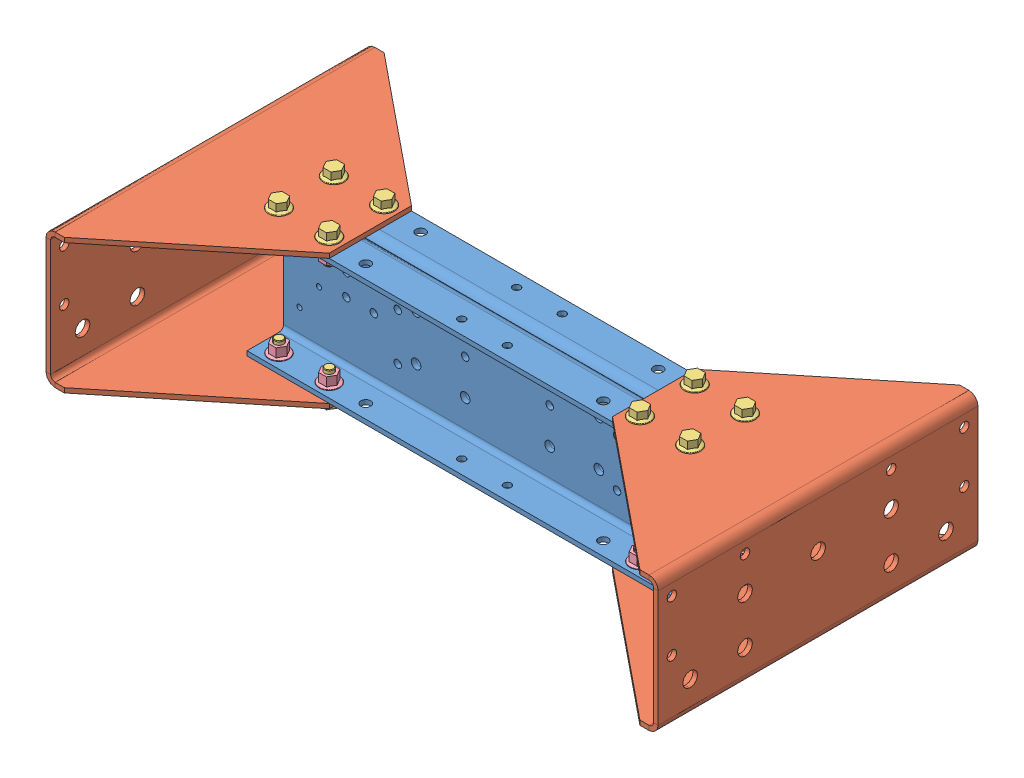
SolidWorks assembly SUB-1700-073, configuration Collapsed. Lengths in mm.
Overall size (850.9 213.23 444.5).
36 component instances, 4 part files, 109 mates.
Components (placement in the parent):
- 2504-CC2-1: 2504-CC2 [Default] at origin size (622.3 174.62 57.15)
- 2504-CC2-2: 2504-CC2 [Default] x (-1 0 0) z (0 0 -1) size (622.3 174.62 57.15)
- 2522-CC2-4: 2522-CC2 [2522-CC2-001] at (425.45 0 0) size (228.6 187.33 444.5)
- 2522-CC2-5: 2522-CC2 [2522-CC2-001] at (-425.45 0 0) x (-1 0 0) z (0 0 -1) size (228.6 187.33 444.5)
- 08130XXXFH8Y-35: 08130XXXFH8Y [08130125FH8Y] at (215.9 -93.6625 38.1) x (-0.866025 0 -0.5) z (0 -1 0) size (28.77 28.77 44.7)
- 08130XXXFH8Y-37: 08130XXXFH8Y [08130125FH8Y] at (-215.9 -93.6625 38.1) x (-0.866025 0 -0.5) z (0 -1 0) size (28.77 28.77 44.7)
- 08130XXXFH8Y-40: 08130XXXFH8Y [08130125FH8Y] at (-215.9 -93.6625 -38.1) x (-0.866025 0 -0.5) z (0 -1 0) size (28.77 28.77 44.7)
- 08130XXXFH8Y-38: 08130XXXFH8Y [08130125FH8Y] at (-215.9 93.6625 38.1) x (-0.866025 0 -0.5) z (0 1 0) size (28.77 28.77 44.7)
- 08130XXXFH8Y-34: 08130XXXFH8Y [08130125FH8Y] at (215.9 93.6625 -38.1) x (0 0 -1) z (0 1 0) size (28.77 28.77 44.7)
- 08130XXXFH8Y-33: 08130XXXFH8Y [08130125FH8Y] at (215.9 -93.6625 -38.1) x (-0.866025 0 -0.5) z (0 -1 0) size (28.77 28.77 44.7)
- 08130XXXFH8Y-36: 08130XXXFH8Y [08130125FH8Y] at (215.9 93.6625 38.1) x (0 0 -1) z (0 1 0) size (28.77 28.77 44.7)
- 08130XXXFH8Y-39: 08130XXXFH8Y [08130125FH8Y] at (-215.9 93.6625 -38.1) x (-0.866025 0 -0.5) z (0 1 0) size (28.77 28.77 44.7)
- XXXXFLN8Y-9: XXXXFLN8Y [0813FLN8Y] at (-285.75 80.9625 38.1) x (-0.866025 0 -0.5) z (0 -1 0) size (28.18 28.18 14.1)
- XXXXFLN8Y-5: XXXXFLN8Y [0813FLN8Y] at (-285.75 -80.9625 -38.1) x (0 0 -1) z (0 1 0) size (28.18 28.18 14.1)
- XXXXFLN8Y-11: XXXXFLN8Y [0813FLN8Y] at (-215.9 80.9625 38.1) x (-0.866025 0 -0.5) z (0 -1 0) size (28.18 28.18 14.1)
- XXXXFLN8Y-6: XXXXFLN8Y [0813FLN8Y] at (-285.75 -80.9625 38.1) x (0 0 -1) z (0 1 0) size (28.18 28.18 14.1)
- XXXXFLN8Y-10: XXXXFLN8Y [0813FLN8Y] at (-215.9 80.9625 -38.1) x (0.866025 0 -0.5) z (0 -1 0) size (28.18 28.18 14.1)
- XXXXFLN8Y-8: XXXXFLN8Y [0813FLN8Y] at (-285.75 80.9625 -38.1) x (-0.866025 0 -0.5) z (0 -1 0) size (28.18 28.18 14.1)
- XXXXFLN8Y-2: XXXXFLN8Y [0813FLN8Y] at (-215.9 -80.9625 -38.1) x (0.866025 0 -0.5) z (0 1 0) size (28.18 28.18 14.1)
- XXXXFLN8Y-4: XXXXFLN8Y [0813FLN8Y] at (215.9 -80.9625 38.1) x (0 0 -1) z (0 1 0) size (28.18 28.18 14.1)
- XXXXFLN8Y-15: XXXXFLN8Y [0813FLN8Y] at (285.75 80.9625 -38.1) x (0 0 -1) z (0 -1 0) size (28.18 28.18 14.1)
- XXXXFLN8Y-1: XXXXFLN8Y [0813FLN8Y] at (215.9 80.9625 -38.1) x (0 0 -1) z (0 -1 0) size (28.18 28.18 14.1)
- XXXXFLN8Y-3: XXXXFLN8Y [0813FLN8Y] at (215.9 -80.9625 -38.1) x (0 0 -1) z (0 1 0) size (28.18 28.18 14.1)
- XXXXFLN8Y-16: XXXXFLN8Y [0813FLN8Y] at (285.75 80.9625 38.1) x (0 0 -1) z (0 -1 0) size (28.18 28.18 14.1)
- XXXXFLN8Y-12: XXXXFLN8Y [0813FLN8Y] at (-215.9 -80.9625 38.1) x (0 0 -1) z (0 1 0) size (28.18 28.18 14.1)
- XXXXFLN8Y-13: XXXXFLN8Y [0813FLN8Y] at (285.75 -80.9625 38.1) x (0 0 -1) z (0 1 0) size (28.18 28.18 14.1)
- XXXXFLN8Y-7: XXXXFLN8Y [0813FLN8Y] at (215.9 80.9625 38.1) x (0 0 -1) z (0 -1 0) size (28.18 28.18 14.1)
- XXXXFLN8Y-14: XXXXFLN8Y [0813FLN8Y] at (285.75 -80.9625 -38.1) x (0 0 -1) z (0 1 0) size (28.18 28.18 14.1)
- 08130XXXFH8Y-26: 08130XXXFH8Y [08130125FH8Y] at (-285.75 -93.6625 38.1) x (-0.866025 0 -0.5) z (0 -1 0) size (28.77 28.77 44.7)
- 08130XXXFH8Y-41: 08130XXXFH8Y [08130125FH8Y] at (-285.75 -93.6625 -38.1) x (-0.866025 0 -0.5) z (0 -1 0) size (28.77 28.77 44.7)
- 08130XXXFH8Y-42: 08130XXXFH8Y [08130125FH8Y] at (-285.75 93.6625 38.1) x (-0.866025 0 -0.5) z (0 1 0) size (28.77 28.77 44.7)
- 08130XXXFH8Y-43: 08130XXXFH8Y [08130125FH8Y] at (-285.75 93.6625 -38.1) x (-0.866025 0 -0.5) z (0 1 0) size (28.77 28.77 44.7)
- 08130XXXFH8Y-44: 08130XXXFH8Y [08130125FH8Y] at (285.75 93.6625 38.1) x (0 0 -1) z (0 1 0) size (28.77 28.77 44.7)
- 08130XXXFH8Y-45: 08130XXXFH8Y [08130125FH8Y] at (285.75 93.6625 -38.1) x (0 0 -1) z (0 1 0) size (28.77 28.77 44.7)
- 08130XXXFH8Y-46: 08130XXXFH8Y [08130125FH8Y] at (285.75 -93.6625 -38.1) x (-0.866025 0 -0.5) z (0 -1 0) size (28.77 28.77 44.7)
- 08130XXXFH8Y-47: 08130XXXFH8Y [08130125FH8Y] at (285.75 -93.6625 38.1) x (-0.866025 0 -0.5) z (0 -1 0) size (28.77 28.77 44.7)
Mates (geometry in assembly coordinates):
- Coincident1: coincident aligned: plane of 2504-CC2-1 through (0 0 0) normal (0 0 1)
- Coincident88: coincident aligned: unknown of 2504-CC2-1
- Coincident3: coincident aligned: unknown of 2504-CC2-1
- Concentric31: concentric anti-aligned: cylinder of ?; circle of ?
- Concentric32: concentric anti-aligned: cylinder of ?; circle of ?
- Concentric33: concentric anti-aligned: cylinder of ?; circle of ?
- Concentric35: concentric anti-aligned: cylinder of ?; circle of ?
- Concentric36: concentric anti-aligned: cylinder of ?; circle of ?
- Concentric37: concentric anti-aligned: cylinder of ?; circle of ?
- Concentric38: concentric anti-aligned: cylinder of ?; circle of ?
- Concentric39: concentric anti-aligned: cylinder of ?; circle of ?
- Parallel7: parallel aligned: plane of ?; plane of ?
- Parallel8: parallel aligned: plane of ?; plane of ?
- Parallel9: parallel aligned: plane of ?; plane of ?
- Parallel10: parallel aligned: plane of ?; plane of ?
- Parallel11: parallel anti-aligned: plane of ?; plane of ?
- Parallel12: parallel aligned: plane of ?; plane of ?
- Parallel13: parallel aligned: plane of ?; plane of ?
- Parallel14: parallel aligned: plane of ?; plane of ?
- Parallel15: parallel anti-aligned: plane of ?; plane of ?
- Parallel16: parallel aligned: plane of ?; plane of ?
- Parallel18: parallel aligned: plane of ?; plane of ?
- Parallel20: parallel aligned: plane of ?; plane of ?
- Parallel21: parallel aligned: plane of ?; plane of ?
- Parallel24: parallel aligned: plane of ?; plane of ?
- Parallel25: parallel aligned: plane of ?; plane of ?
- Parallel26: parallel aligned: plane of ?; plane of ?
- Parallel27: parallel aligned: plane of ?; plane of ?
- Parallel28: parallel aligned: plane of ?; plane of ?
- Parallel30: parallel aligned: plane of ?; plane of ?
- Parallel33: parallel aligned: plane of ?; plane of ?
- Parallel34: parallel aligned: plane of ?; plane of ?
- Parallel35: parallel aligned: plane of ?; plane of ?
- Parallel36: parallel aligned: plane of ?; plane of ?
- Coincident57: coincident aligned: plane of 2504-CC2-1 through (0 0 0) normal (0 1 0); plane of 2504-CC2-2 through (0 0 0) normal (0 1 0)
- Coincident58: coincident anti-aligned: plane of 2504-CC2-1 through (0 0 0) normal (1 0 0); plane of 2504-CC2-2 through (0 0 0) normal (-1 0 0)
- Concentric40: concentric aligned: unknown of 2522-CC2-5
- Concentric41: concentric aligned: unknown of 2522-CC2-5
- Coincident66: coincident aligned: plane of ?; plane of ?
- Coincident67: coincident aligned: plane of ?; plane of ?
- Coincident68: coincident aligned: plane of ?; plane of ?
- Coincident70: coincident anti-aligned: unknown of 2504-CC2-2
- Concentric42: concentric anti-aligned: unknown of 2522-CC2-5
- Coincident71: coincident aligned: plane of ?; plane of ?
- Coincident72: coincident aligned: plane of ?; plane of ?
- Coincident73: coincident aligned: plane of ?; plane of ?
- Coincident74: coincident anti-aligned: unknown of 2504-CC2-1
- Concentric43: concentric anti-aligned: unknown of 2522-CC2-5
- Concentric44: concentric aligned: unknown of 2522-CC2-4
- Concentric47: concentric aligned: unknown of 2522-CC2-4
- Coincident79: coincident aligned: plane of ?; plane of ?
- Coincident80: coincident aligned: plane of ?; plane of ?
- Coincident81: coincident aligned: plane of ?; plane of ?
- Coincident82: coincident anti-aligned: unknown of 2504-CC2-2
- Coincident83: coincident aligned: plane of ?; plane of ?
- Coincident84: coincident aligned: plane of ?; plane of ?
- Coincident85: coincident aligned: plane of ?; plane of ?
- Coincident86: coincident anti-aligned: unknown of 2504-CC2-2
- Parallel37: parallel aligned: plane of ?; plane of ?
- Coincident94: coincident anti-aligned: unknown of 2522-CC2-5
- Coincident95: coincident anti-aligned: unknown of 2522-CC2-5
- Coincident96: coincident anti-aligned: unknown of 2522-CC2-5
- Coincident97: coincident anti-aligned: unknown of 2522-CC2-5
- Coincident100: coincident anti-aligned: unknown of 2522-CC2-4
- Coincident101: coincident anti-aligned: unknown of 2522-CC2-4
- Concentric63: concentric anti-aligned: unknown of 2522-CC2-4
- Concentric66: concentric anti-aligned: unknown of 2522-CC2-4
- Coincident104: coincident anti-aligned: unknown of 2522-CC2-4
- Coincident105: coincident anti-aligned: unknown of 2522-CC2-4
- Coincident106: coincident anti-aligned: plane of 2504-CC2-1 through (0 0 0) normal (0 0 1); plane of 2504-CC2-2 through (0 0 0) normal (0 0 -1)
- Coincident107: coincident aligned: unknown of 2522-CC2-4
- Coincident108: coincident aligned: unknown of 2522-CC2-4
- Distance1: distance = 425.45 mm aligned: unknown of 2522-CC2-4
- Coincident109: coincident anti-aligned: unknown of 2522-CC2-5
- Coincident110: coincident aligned: unknown of 2522-CC2-5
- Distance2: distance = 425.45 mm anti-aligned: unknown of 2522-CC2-5
- Concentric67: concentric aligned: unknown of 2504-CC2-2
- Concentric68: concentric aligned: unknown of 2504-CC2-2
- Concentric69: concentric aligned: unknown of 2504-CC2-1
- Concentric70: concentric aligned: unknown of 2504-CC2-1
- Concentric71: concentric aligned: unknown of 2504-CC2-2
- Concentric72: concentric aligned: unknown of 2504-CC2-1
- Concentric73: concentric aligned: unknown of 2504-CC2-1
- Concentric74: concentric aligned: unknown of 2504-CC2-2
- Parallel38: parallel aligned: plane of ?; plane of assembly
- Concentric75: concentric anti-aligned: unknown of 2522-CC2-5
- Concentric76: concentric anti-aligned: unknown of 2522-CC2-5
- Coincident113: coincident anti-aligned: unknown of 2522-CC2-5
- Coincident114: coincident anti-aligned: unknown of 2522-CC2-5
- Concentric77: concentric aligned: unknown of 2522-CC2-5
- Concentric78: concentric aligned: unknown of 2522-CC2-5
- Coincident115: coincident anti-aligned: unknown of 2522-CC2-5
- Coincident116: coincident anti-aligned: unknown of 2522-CC2-5
- Concentric79: concentric aligned: unknown of 2522-CC2-4
- Concentric80: concentric aligned: unknown of 2522-CC2-4
- Coincident117: coincident anti-aligned: unknown of 2522-CC2-4
- Coincident118: coincident anti-aligned: unknown of 2522-CC2-4
- Concentric81: concentric anti-aligned: unknown of 2522-CC2-4
- Concentric82: concentric anti-aligned: unknown of 2522-CC2-4
- Coincident119: coincident anti-aligned: unknown of 2522-CC2-4
- Coincident120: coincident anti-aligned: unknown of 2522-CC2-4
- Parallel39: parallel: line of ?; plane of assembly
- Parallel40: parallel: line of ?; plane of assembly
- Parallel41: parallel: line of ?; plane of assembly
- Parallel42: parallel: line of ?; plane of assembly
- Parallel43: parallel: line of ?; plane of assembly
- Parallel44: parallel: line of ?; plane of assembly
- Parallel45: parallel: line of ?; plane of assembly
- Parallel46: parallel: 
